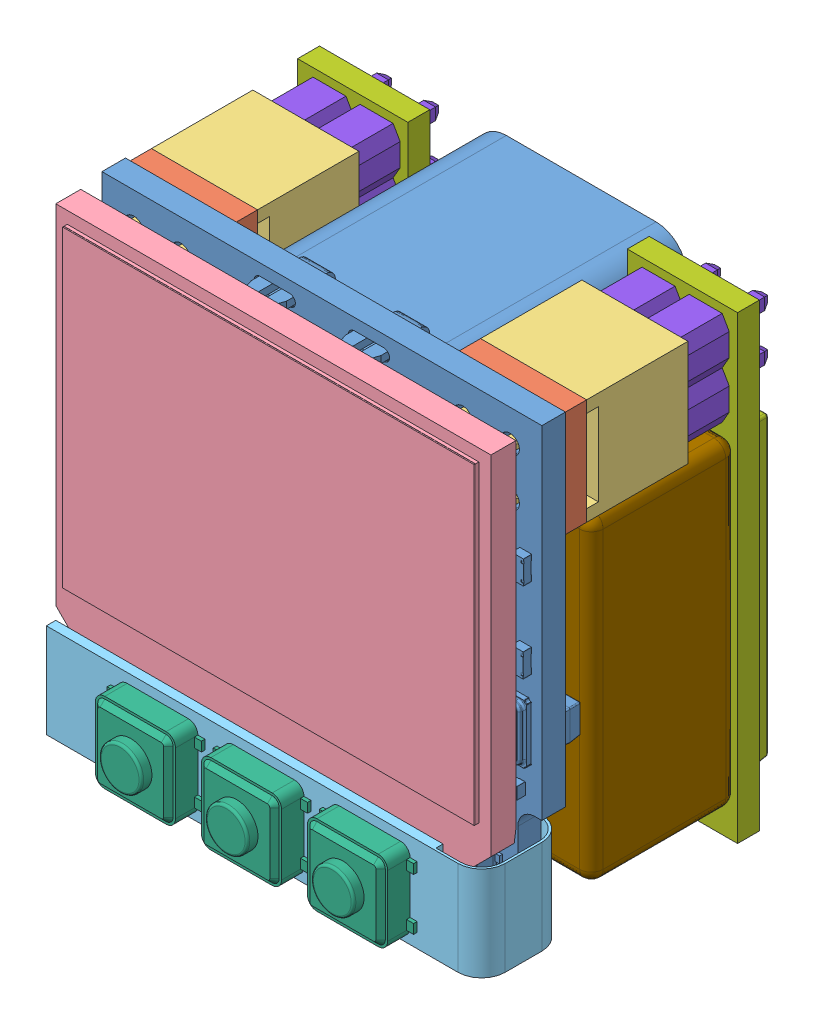
SolidWorks assembly SAU-G0+EX_AHT-PL_PCB, configuration 默认. Lengths in mm.
Overall size (20.36 19.5 16.09).
17 component instances, 9 part files, 6 mates.
Components (placement in the parent):
- SAU-G0_PCB-1: SAU-G0_PCB [默认] at (11.8444 27.5987 -11.0527) size (20.36 19.5 15.06)
  - SAU-G0_STEP_AD-1: SAU-G0_STEP_AD [默认] at (-16.5787 -13.328 24.4103) size (18.66 19.5 12.19)
  - 2.00mm_2x2_垫板PCB_厚1.0mm-1: 2.00mm_2x2_垫板PCB_厚1.0mm [默认] at (3.1013 6.262 22.4106) x (1 0 0) z (0 -1 0) size (4.5 1 4.5)
  - 2.00mm母座2x2-1: 2.00mm母座2x2 [Default] at (4.1013 6.262 18.1106) x (1 0 0) z (0 1 0) size (4.5 7.1 4.5)
  - 2.00mm_2x2_垫板PCB_厚1.0mm-2: 2.00mm_2x2_垫板PCB_厚1.0mm [默认] at (-10.8587 6.262 22.4106) x (-1 0 0) z (0 1 0) size (4.5 1 4.5)
  - 2.00mm母座2x2-2: 2.00mm母座2x2 [Default] at (-11.8587 6.262 18.1106) x (-1 0 0) z (0 -1 0) size (4.5 7.1 4.5)
  - 0.66寸_64x48_TOP_FPC背面距离背板1mm-1: 0.66寸_64x48_TOP_FPC背面距离背板1mm [Default] at (-3.8787 8.514 25.9703) x (1 0 0) z (0 -1 0) size (18.46 2.27 19.3)
  - 轻触开关+柔性PCB-1: 轻触开关+柔性PCB [默认] at (-0.958 10.42 26.3367) x (1 0 0) z (0 -1 0) size (20.26 5.16 4.01)
    - 方案2-轻触开关_柔性PCB-1: 方案2-轻触开关_柔性PCB [默认] at (-12.1506 0.4339 17.21) size (20.26 3.56 4.01)
    - 轻触开关3x3.5x1.5_3x4.0x2.0-1: 轻触开关3x3.5x1.5_3x4.0x2.0 [默认] at (-2.9206 0.5339 19.31) size (4 1.6 3.4)
    - 轻触开关3x3.5x1.5_3x4.0x2.0-2: 轻触开关3x3.5x1.5_3x4.0x2.0 [默认] at (1.5794 0.5339 19.31) size (4 1.6 3.4)
    - 轻触开关3x3.5x1.5_3x4.0x2.0-3: 轻触开关3x3.5x1.5_3x4.0x2.0 [默认] at (-7.4206 0.5339 19.31) size (4 1.6 3.4)
- SAU-G0-EX_AHT-PL_PCB-1: SAU-G0-EX_AHT-PL_PCB [默认] at (-1.3662 16.7088 5.0579) x (-1 0 0) z (0 0 -1) size (18.66 19.5 9.43)
  - SAU-G0-EX_AHT-PL_STEP_AD-1: SAU-G0-EX_AHT-PL_STEP_AD [默认] at (23.688 -2.438 0) x (-1 0 0) z (0 0 -1) size (18.66 19.5 3.73)
  - 2.0mm排针2x2-1: 2.0mm排针2x2 [Default] at (-1.352 18.152 0) x (1 0 0) z (0 1 0) size (4 8.2 4)
  - 2.0mm排针2x2-2: 2.0mm排针2x2 [Default] at (-17.312 16.152 0) x (-1 0 0) z (0 -1 0) size (4 8.2 4)
- 601419(18.5x13.5x6.2mm)_3.7V_100mAh-1: 601419(18.5x13.5x6.2mm)_3.7V_100mAh [Default] at (17.2978 24.8608 6.9079) x (0 -1 0) z (-1 0 0) size (13.5 6.2 18)
Mates (geometry in assembly coordinates):
- 重合1: coincident aligned: plane of SAU-G0_PCB-1/SAU-G0_STEP_AD-1 through (17.2978 36.2128 12.3579) normal (1 0 0); plane of SAU-G0-EX_AHT-PL_PCB-1/SAU-G0-EX_AHT-PL_STEP_AD-1 through (17.2978 16.7088 4.1282) normal (1 0 0)
- 重合2: coincident anti-aligned: plane of SAU-G0-EX_AHT-PL_PCB-1/2.0mm排针2x2-2 through (15.9458 32.8608 7.0579) normal (0 0 1); plane of SAU-G0_PCB-1/2.00mm母座2x2-1 through (16.9458 36.1108 7.0579) normal (0 0 -1)
- 重合3: coincident aligned: plane of SAU-G0_PCB-1/SAU-G0_STEP_AD-1 through (-1.3662 36.2128 12.3579) normal (0 1 0); plane of SAU-G0-EX_AHT-PL_PCB-1/SAU-G0-EX_AHT-PL_STEP_AD-1 through (17.2978 36.2128 4.1282) normal (0 1 0)
- 重合4: coincident: plane of SAU-G0_PCB-1/2.00mm母座2x2-1 through (16.9458 31.6108 7.0579) normal (0 -1 0); plane of 601419(18.5x13.5x6.2mm)_3.7V_100mAh-1 through (17.2978 31.6108 6.9079) normal (0 1 0)
- 重合5: coincident: plane of SAU-G0-EX_AHT-PL_PCB-1/SAU-G0-EX_AHT-PL_STEP_AD-1 through (17.2978 16.7088 4.1282) normal (1 0 0); plane of 601419(18.5x13.5x6.2mm)_3.7V_100mAh-1 through (17.2978 18.1108 5.0579) normal (1 0 0)
- 重合6: coincident anti-aligned: plane of SAU-G0-EX_AHT-PL_PCB-1/SAU-G0-EX_AHT-PL_STEP_AD-1 through (7.2313 25.9303 5.0579) normal (0 0 1); plane of 601419(18.5x13.5x6.2mm)_3.7V_100mAh-1 through (17.2978 18.1108 5.0579) normal (0 0 -1)
